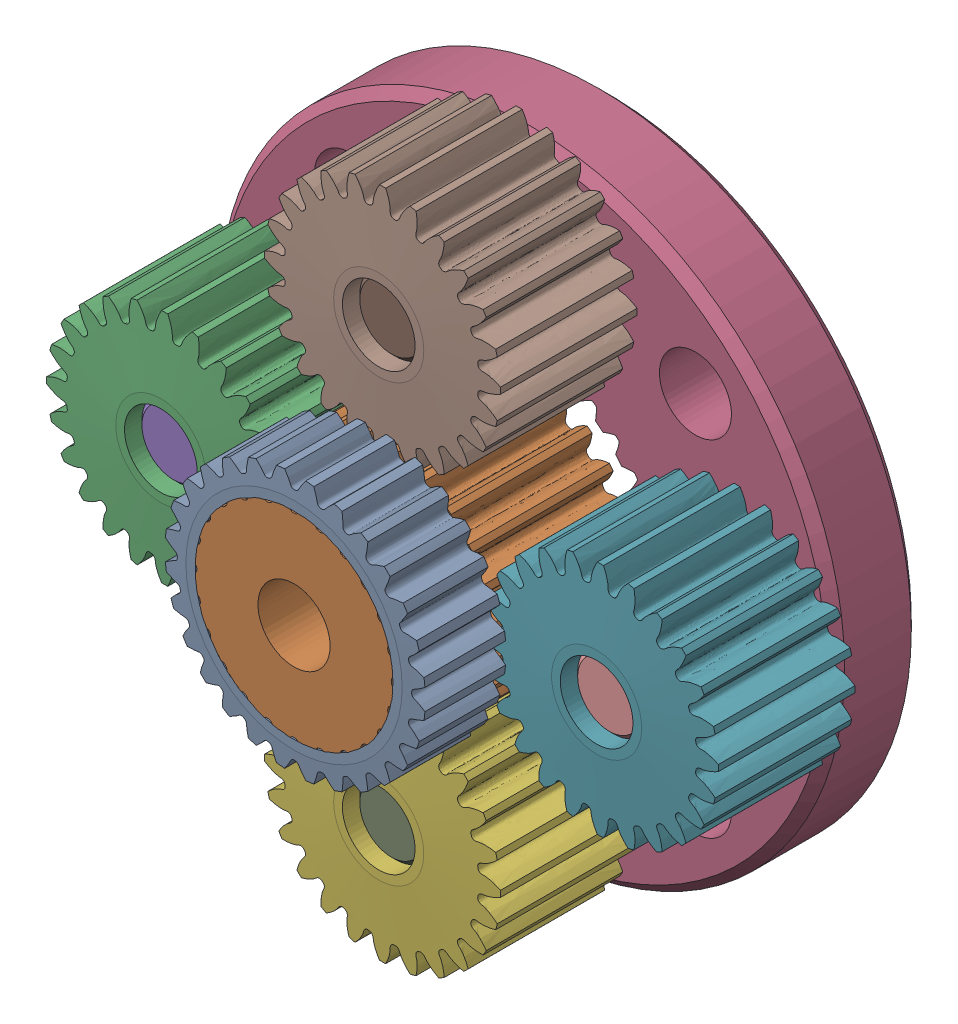
SolidWorks assembly 217-2818 Rev1, configuration Default. Lengths in mm.
Overall size (49.07 49.07 17.4).
10 component instances, 4 part files, 0 mates.
Components (placement in the parent):
- 217-2725-001 Rev1_24t Sun-1: 217-2725-001 Rev1_24t Sun [Default] at (0 0 8.7) size (14.45 14.45 12.7)
- 217-2725-002 Rev1_24t Planet-1: 217-2725-002 Rev1_24t Planet [Default] at (-12.089 0 6.35) x (-0.130526 0.991445 0) z (0 0 -1) size (13.17 13.15 8)
- 217-2724-002 Rev1-1: 217-2724-002 Rev1 [Default] x (0.707107 -0.707107 0) z (0 0 -1) size (34.7 34.7 4.7)
- 217-2625-010 Rev1_1-1: 217-2625-010 Rev1_1 [Default] at (-12.089 0 3.65) x (0.971612 -0.236582 0) z (0 0 1) size (4 4 12)
- 217-2725-002 Rev1_24t Planet-2: 217-2725-002 Rev1_24t Planet [Default] at (0 -12.089 6.35) x (-0.991445 -0.130526 0) z (0 0 -1) size (13.17 13.15 8)
- 217-2725-002 Rev1_24t Planet-3: 217-2725-002 Rev1_24t Planet [Default] at (12.089 0 6.35) x (0.130526 -0.991445 0) z (0 0 -1) size (13.17 13.15 8)
- 217-2725-002 Rev1_24t Planet-4: 217-2725-002 Rev1_24t Planet [Default] at (0 12.089 6.35) x (0.991445 0.130526 0) z (0 0 -1) size (13.17 13.15 8)
- 217-2625-010 Rev1_1-2: 217-2625-010 Rev1_1 [Default] at (0 -12.089 3.65) x (0.236582 0.971612 0) z (0 0 1) size (4 4 12)
- 217-2625-010 Rev1_1-3: 217-2625-010 Rev1_1 [Default] at (12.089 0 3.65) x (-0.971612 0.236582 0) z (0 0 1) size (4 4 12)
- 217-2625-010 Rev1_1-4: 217-2625-010 Rev1_1 [Default] at (0 12.089 3.65) x (-0.236582 -0.971612 0) z (0 0 1) size (4 4 12)
